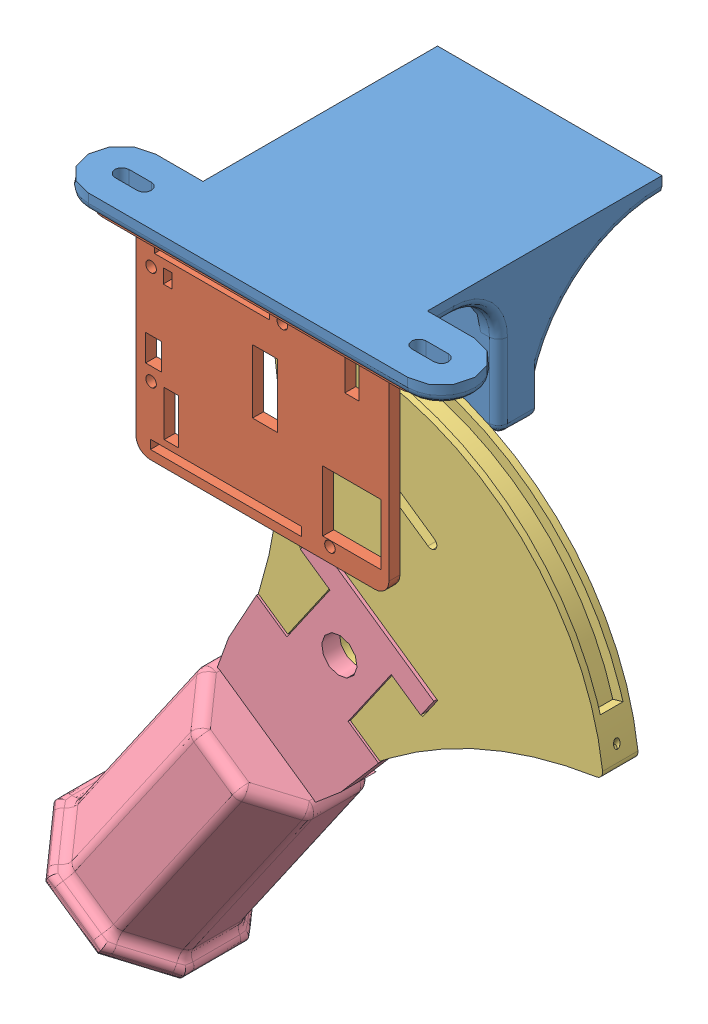
SolidWorks assembly ungr_hapkit, configuration Default. Lengths in mm.
Overall size (167.96 203.49 85.38).
4 component instances, 4 part files, 11 mates.
Components (placement in the parent):
- project_base_v2 - Copy-1: project_base_v2 - Copy [Default] x (-1 0 0) z (0 0 1) size (109.37 119.69 85.38)
- project_hapkit_board_v3-1: project_hapkit_board_v3 [Default] at (-3.175 -4.6216 33.1718) x (-1 0 0) z (0 0 1) size (95 59.49 11)
- Hapkit3_0_Sector-1: Hapkit3_0_Sector [Default] at (0 -98.584 8.38) x (-0.821823 0.569744 0) z (0 0 1) size (113.37 109.9 10.02)
- project_handle_tennis-1: project_handle_tennis [Default] at (0 -98.584 18.38) x (0.821823 -0.569744 0) z (0 0 -1) size (44.23 123.07 44.23)
Mates (geometry in assembly coordinates):
- Coincident2: coincident aligned: plane of project_base_v2 - Copy-1 through (0 0 0) normal (0 0 1)
- Coincident3: coincident anti-aligned: plane of project_base_v2 - Copy-1 through (0 0 0) normal (0 -1 0)
- Coincident4: coincident anti-aligned: plane of project_base_v2 - Copy-1 through (0 0 0) normal (-1 0 0)
- Concentric1: concentric aligned: cylinder of project_base_v2 - Copy-1 through (38.825 116.0968 34.7218) axis (0 -1 0) radius 2; cylinder of project_hapkit_board_v3-1 through (38.825 0 34.7218) axis (0 -1 0) radius 2.0635
- Concentric2: concentric aligned: cylinder of project_base_v2 - Copy-1 through (-45.175 116.0968 34.7218) axis (0 -1 0) radius 2; cylinder of project_hapkit_board_v3-1 through (-45.175 0 34.7218) axis (0 -1 0) radius 2.0635
- Coincident5: coincident anti-aligned: plane of project_base_v2 - Copy-1 through (0 0 0) normal (0 -1 0); plane of project_hapkit_board_v3-1 through (38.825 0 34.7218) normal (0 1 0)
- Concentric3: concentric anti-aligned: cylinder of project_base_v2 - Copy-1 through (0 -98.584 5.08) axis (0 0 -1) radius 2.286; cylinder of Hapkit3_0_Sector-1 through (0 -98.584 8.38) axis (0 0 1) radius 5
- Concentric4: concentric anti-aligned: cylinder of project_base_v2 - Copy-1 through (0 -98.584 5.08) axis (0 0 -1) radius 2.286; cylinder of project_handle_tennis-1 through (0 -98.584 13.38) axis (0 0 1) radius 5
- Distance1: distance = 3.3 mm anti-aligned: plane of Hapkit3_0_Sector-1 through (-90.2172 -100.8528 8.38) normal (0 0 -1); plane of project_base_v2 - Copy-1 through (0 0 5.08) normal (0 0 1)
- Coincident8: coincident anti-aligned: plane of Hapkit3_0_Sector-1 through (0 -98.584 8.38) normal (-0.821823 0.569744 0); plane of project_handle_tennis-1 through (0 -98.584 18.38) normal (0.821823 -0.569744 0)
- Coincident9: coincident anti-aligned: plane of Hapkit3_0_Sector-1 through (111.2551 -244.7345 13.38) normal (0 0 1); plane of project_handle_tennis-1 through (0 -98.584 13.38) normal (0 0 -1)
